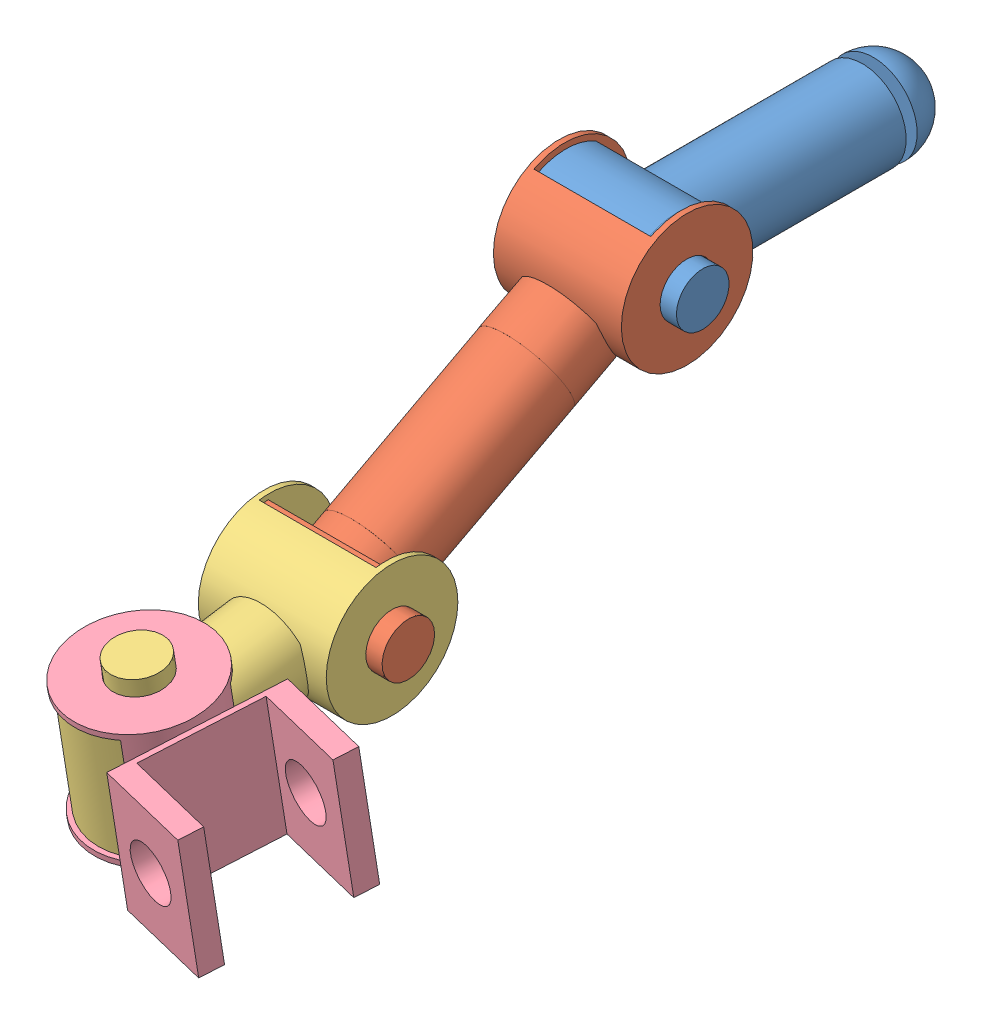
SolidWorks assembly legleft, configuration Default. Lengths in mm.
Overall size (120.18 165.61 405.62).
4 component instances, 4 part files, 6 mates.
Components (placement in the parent):
- Part1-1: Part1 [Default] at (-55.9435 85.7723 123.5115) size (73.34 55.31 161.39)
- Part2-1: Part2 [Default] at (-85.1535 85.7723 237.698) x (0 -0.884015 -0.467458) z (0 -0.467458 0.884015) size (60.1 73.34 210.23)
- Part3-1: Part3 [Default] at (-85.1535 14.5374 372.4112) x (0 -0.987296 -0.158895) z (0 -0.158895 0.987296) size (73.34 58.42 140.58)
- Part4-1: Part4 [Default] at (-55.9435 -27.4384 449.3963) x (0.216262 0.155135 -0.963932) z (0.976335 -0.034363 0.213514) size (70 60 107.59)
Mates (geometry in assembly coordinates):
- Concentric1: concentric anti-aligned: cylinder of Part1-1 through (-92.6135 85.7723 237.698) axis (1 0 0) radius 12; cylinder of Part2-1 through (-82.6135 85.7723 237.698) axis (-1 0 0) radius 12
- Coincident1: coincident anti-aligned: plane of Part1-1 through (-82.6135 85.5313 237.1915) normal (-1 0 0); plane of Part2-1 through (-82.6135 85.7723 237.698) normal (1 0 0)
- Concentric3: concentric anti-aligned: cylinder of Part2-1 through (-92.6135 14.5374 372.4112) axis (1 0 0) radius 12; cylinder of Part3-1 through (-82.6135 14.5374 372.4112) axis (-1 0 0) radius 12
- Coincident2: coincident anti-aligned: plane of Part2-1 through (-82.6135 14.8664 371.789) normal (-1 0 0); plane of Part3-1 through (-82.6135 14.5374 372.4112) normal (1 0 0)
- Concentric4: concentric anti-aligned: cylinder of Part3-1 through (-55.9435 -34.8037 448.211) axis (0 0.987296 0.158895) radius 12; cylinder of Part4-1 through (-55.9435 -24.9307 449.7999) axis (0 -0.987296 -0.158895) radius 12
- Coincident3: coincident anti-aligned: plane of Part3-1 through (-55.9435 -24.773 448.8198) normal (0 -0.987296 -0.158895); plane of Part4-1 through (-55.9435 -24.9307 449.7999) normal (0 0.987296 0.158895)
